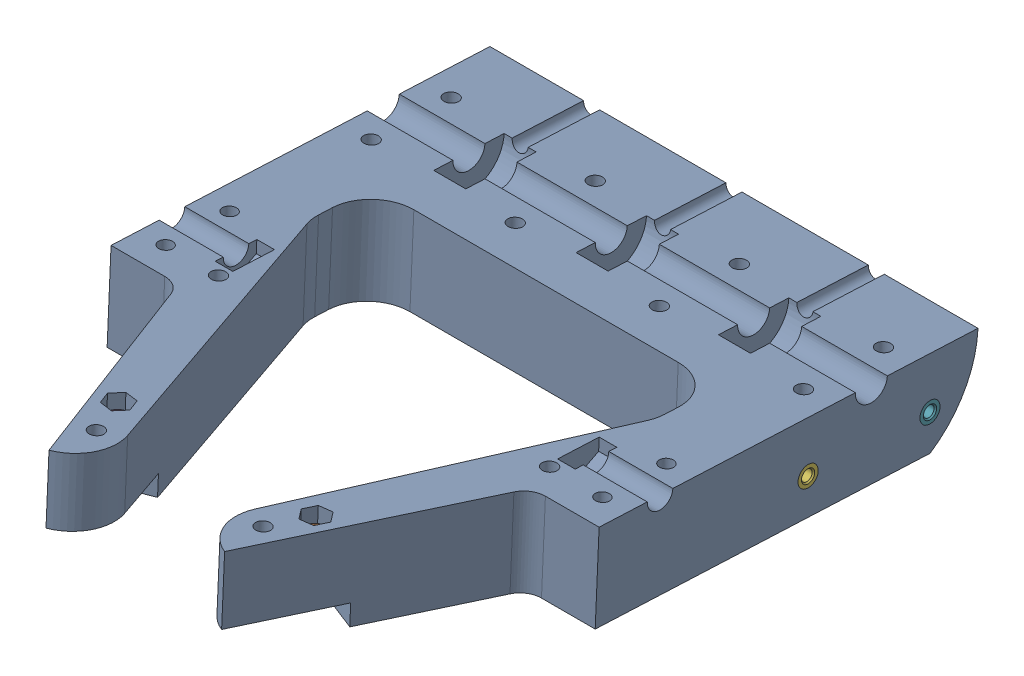
SolidWorks assembly Main Casing A Pre-Asmbly, configuration Default. Lengths in mm.
Overall size (152.4 35.57 187.69).
11 component instances, 4 part files, 0 mates.
Components (placement in the parent):
- Main Casing A-1: Main Casing A [Default] at (0 -139.7 43.8404) x (1 0 0) z (0 0.045363 0.998971) size (152.4 27.13 186.65)
- 93625A150-1: 93625A150 [Default] at (30.8014 -142.8781 172.2532) x (0.927184 0.016993 0.374221) z (0 0.998971 -0.045363) size (7 8.08 5)
  - 93625A150_2-1: 93625A150_2 [Default] at origin size (7 8.08 5)
  - 93625A150-1: 93625A150 [Default] at origin size (6.53 6.53 0.53)
- 93625A150-2: 93625A150 [Default] at (-30.8014 -142.8781 172.2532) x (0.927184 -0.016993 -0.374221) z (0 0.998971 -0.045363) size (7 8.08 5)
  - 93625A150_2-1: 93625A150_2 [Default] at origin size (7 8.08 5)
  - 93625A150-1: 93625A150 [Default] at origin size (6.53 6.53 0.53)
- 94180A351-1: 94180A351 [Default] at (76.2 -154.6945 63.5909) x (0 0.045363 0.998971) z (1 0 0) size (6.35 6.35 4.7)
- 94180A351-2: 94180A351 [Default] at (76.2 -156.4228 25.5301) x (0 0.045363 0.998971) z (1 0 0) size (6.35 6.35 4.7)
- 94180A351-3: 94180A351 [Default] at (-76.2 -154.6945 63.5909) x (0 -0.045363 -0.998971) z (-1 0 0) size (6.35 6.35 4.7)
- 94180A351-4: 94180A351 [Default] at (-76.2 -156.4228 25.5301) x (0 -0.045363 -0.998971) z (-1 0 0) size (6.35 6.35 4.7)
